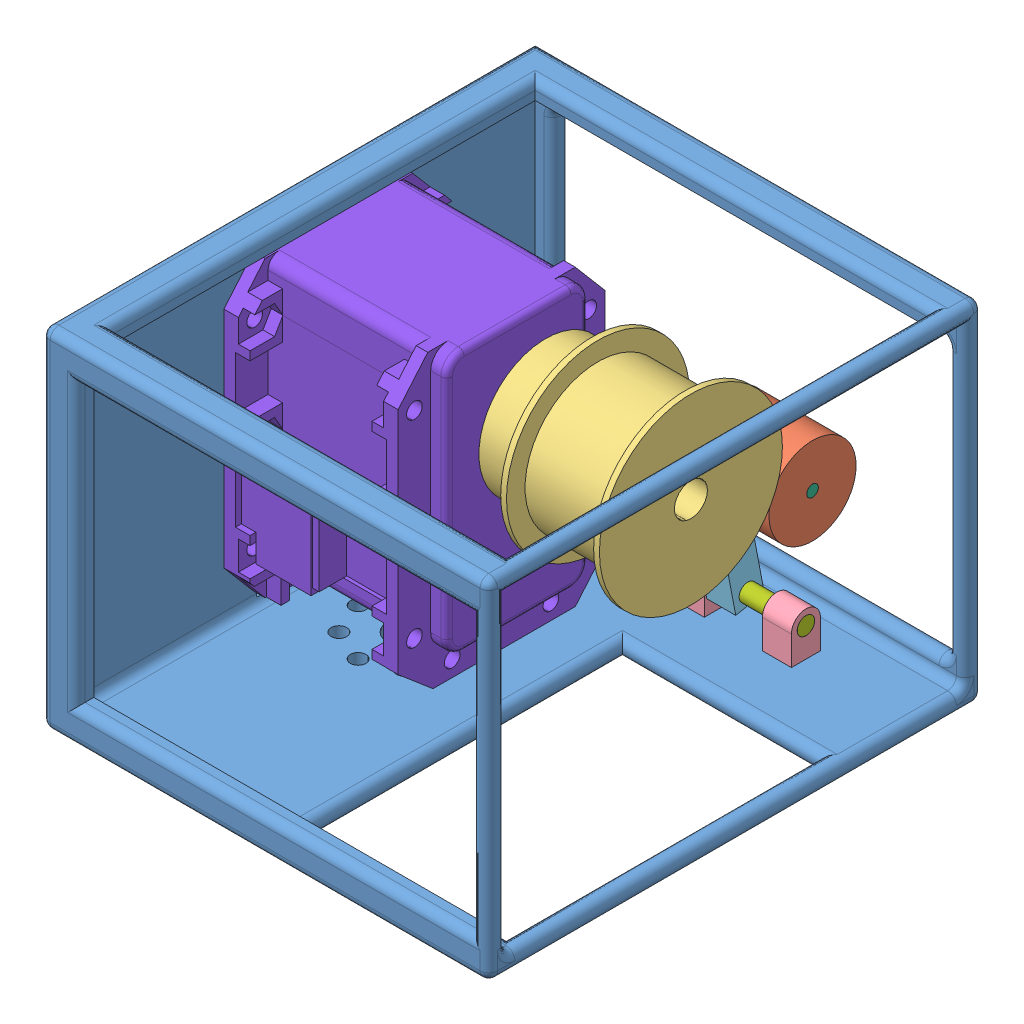
SolidWorks assembly Assemblage2, configuration Défaut. Lengths in mm.
Overall size (78.25 60 86.19).
9 component instances, 8 part files, 18 mates.
Components (placement in the parent):
- Base main-1: Base main [Défaut] at (-37.3309 -27.4916 43.716) size (77 60 86.19)
- Galet de Guidage-1: Galet de Guidage [Défaut] at (12.2691 6.0504 60.575) x (0 -0.88491 0.465761) z (1 0 0) size (15 15 15)
- Poulie-1: Poulie [Défaut] at (3.2691 16.2084 82.516) x (0 0 -1) z (1 0 0) size (31.5 31.5 25)
- support -1: support  [Défaut] at (16.2691 -24.4916 58.216) x (1 0 0) z (0 1 0) size (5 5 7.5)
- Prismatique-1: Prismatique [Défaut] at (11.2691 8.4823 58.4928) x (0 -0.982382 -0.186883) z (-1 0 0) size (30 5 5)
- Tige1-1: Tige1 [Défaut] at (6.2691 6.0504 60.575) x (0 0 -1) z (1 0 0) size (2 2 21)
- support -2: support  [Défaut] at (1.2691 -24.4916 58.216) x (1 0 0) z (0 1 0) size (5 5 7.5)
- Tige2-1: Tige2 [Défaut] at (1.2691 -19.4916 55.716) x (0 0 -1) z (1 0 0) size (3 3 20)
- Pièce17-1: Pièce17 [Défaut] at (-19.3309 16.2084 82.516) x (0 0 -1) z (1 0 0) size (35.6 50.6 41.85)
Mates (geometry in assembly coordinates):
- Coïncidente1: coincident anti-aligned: plane of Base main-1 through (-34.3309 -27.4916 43.716) normal (1 0 0); plane of Pièce17-1 through (-34.3309 16.2084 82.516) normal (-1 0 0)
- Coaxiale1: concentric aligned: cylinder of Base main-1 through (-34.4309 20.7084 97.516) axis (-1 0 0) radius 1.35; cylinder of Pièce17-1 through (-34.3309 20.7084 97.516) axis (-1 0 0) radius 1.35
- Coaxiale2: concentric aligned: cylinder of Poulie-1 through (3.2691 16.2084 82.516) axis (1 0 0) radius 2.85; cylinder of Pièce17-1 through (-1.5809 16.2084 82.516) axis (1 0 0) radius 2.85
- Coïncidente2: coincident anti-aligned: plane of Poulie-1 through (3.2691 16.2084 71.016) normal (-1 0 0); plane of Pièce17-1 through (3.2691 16.2084 82.516) normal (1 0 0)
- Coïncidente3: coincident anti-aligned: plane of Galet de Guidage-1 through (12.2691 5.1655 61.0408) normal (-1 0 0); plane of Poulie-1 through (12.2691 16.2084 69.966) normal (1 0 0)
- Coaxiale3: concentric anti-aligned: cylinder of Galet de Guidage-1 through (27.2691 6.0504 60.575) axis (-1 0 0) radius 1; cylinder of Tige1-1 through (6.2691 6.0504 60.575) axis (1 0 0) radius 1
- Coïncidente4: coincident aligned: plane of Galet de Guidage-1 through (27.2691 -0.5865 64.0682) normal (1 0 0); plane of Tige1-1 through (27.2691 6.0504 60.575) normal (1 0 0)
- Coaxiale4: concentric anti-aligned: cylinder of Prismatique-1 through (11.2691 6.0504 60.575) axis (-1 0 0) radius 1; cylinder of Tige1-1 through (6.2691 6.0504 60.575) axis (1 0 0) radius 1
- Coïncidente5: coincident aligned: plane of Prismatique-1 through (6.2691 8.4823 58.4928) normal (-1 0 0); plane of Tige1-1 through (6.2691 6.0504 59.575) normal (-1 0 0)
- Coaxiale5: concentric anti-aligned: cylinder of Prismatique-1 through (11.2691 -19.4916 55.716) axis (-1 0 0) radius 1.5; cylinder of Tige2-1 through (1.2691 -19.4916 55.716) axis (1 0 0) radius 1.5
- Coaxiale6: concentric anti-aligned: cylinder of support -1 through (21.2691 -19.4916 55.716) axis (-1 0 0) radius 1.5; cylinder of Tige2-1 through (1.2691 -19.4916 55.716) axis (1 0 0) radius 1.5
- Coïncidente8: coincident aligned: plane of support -1 through (21.2691 -19.4916 55.716) normal (1 0 0); plane of Tige2-1 through (21.2691 -19.4916 55.716) normal (1 0 0)
- Coaxiale7: concentric anti-aligned: cylinder of support -2 through (6.2691 -19.4916 55.716) axis (-1 0 0) radius 1.5; cylinder of Tige2-1 through (1.2691 -19.4916 55.716) axis (1 0 0) radius 1.5
- Coïncidente9: coincident aligned: plane of support -2 through (1.2691 -19.4916 55.716) normal (-1 0 0); plane of Tige2-1 through (1.2691 -19.4916 54.216) normal (-1 0 0)
- Coïncidente10: coincident anti-aligned: plane of Prismatique-1 through (6.2691 8.4823 58.4928) normal (-1 0 0); plane of support -2 through (6.2691 -19.4916 55.716) normal (1 0 0)
- Parallèle1: parallel aligned: plane of support -1 through (21.2691 -24.4916 53.216) normal (0 -1 0); plane of support -2 through (6.2691 -24.4916 53.216) normal (0 -1 0)
- Coïncidente12: coincident anti-aligned: plane of Base main-1 through (-34.3309 -24.4916 125.716) normal (0 1 0); plane of support -1 through (21.2691 -24.4916 53.216) normal (0 -1 0)
- Distance1: distance = 5 mm: plane of support -1 through (21.2691 -19.4916 53.216) normal (0 0 -1); line of Base main-1 through (-32.8309 -24.4916 48.216) axis (1 0 0)
